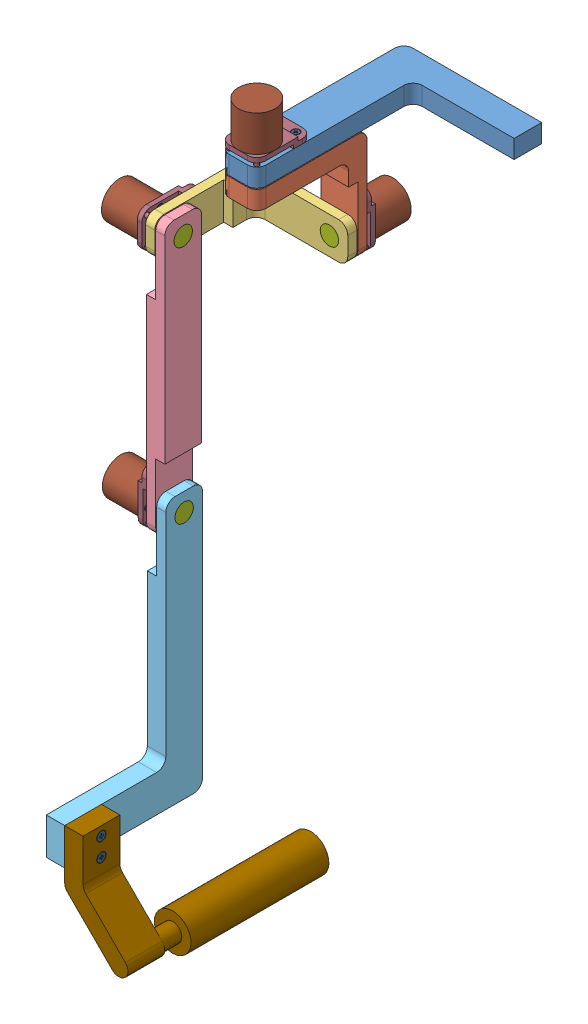
SolidWorks assembly master-arm, configuration Varsayılan. Lengths in mm.
Overall size (278 780.62 311).
52 component instances, 13 part files, 71 mates.
Components (placement in the parent):
- parca-1-1: parca-1 [Varsayılan] at (-105.8908 1.0153 205) x (1 0 0) z (0 1 0) size (150 200 20)
- parca-2-1: parca-2 [Varsayılan] at (-105.8908 -19.9847 230) size (40 120 120)
- parca-3-1: parca-3 [Varsayılan] at (-145.8908 -99.9847 171) size (120 40 120)
- parca-4-1: parca-4 [Varsayılan] at (-204.8908 -229.9847 271) size (20 300 40)
- parca-5-1: parca-5 [Varsayılan] at (-203.8908 -464.9847 271) size (20 290 150)
- pin-1-1: pin-1 [Varsayılan] at (-105.8908 -19.9847 270) size (20 40 20)
- pin-2-1: pin-2 [Varsayılan] at (-204.8908 -99.9847 271) size (20 20 20)
- pin-2-2: pin-2 [Varsayılan] at (-203.8908 -359.9847 271) size (20 20 20)
- pin-2-4: pin-2 [Varsayılan] at (-105.8908 -99.9847 171) x (0 0 1) z (-1 0 0) size (20 20 20)
- instrument ball bearing_68_am-1: instrument ball bearing_68_am [AFBMA 12.1.4.1 - 0200-27 - 28,SI,NC,28_68] at (-203.3908 -99.9847 271) x (-1 0 0) z (0 -0.924225 -0.381849) size (5 27 27)
- instrument ball bearing_68_am-4: instrument ball bearing_68_am [AFBMA 12.1.4.1 - 0200-27 - 28,SI,NC,28_68] at (-202.3908 -359.9847 271) x (-1 0 0) z (0 -0.924225 -0.381849) size (5 27 27)
- instrument ball bearing_68_am-5: instrument ball bearing_68_am [AFBMA 12.1.4.1 - 0200-27 - 28,SI,NC,28_68] at (-105.8908 -99.9847 172.5) x (0 0 -1) z (1 0 0) size (5 27 27)
- instrument ball bearing_68_am-6: instrument ball bearing_68_am [AFBMA 12.1.4.1 - 0200-27 - 28,SI,NC,28_68] at (-105.8908 18.5153 270) x (0 -1 0) z (0 0 1) size (5 27 27)
- parca-6-1: parca-6 [Varsayılan] at (-183.8908 -589.9847 361) x (1 0 0) z (0 -1 0) size (77.48 210 121.62)
- flat head screw_am-3: flat head screw_am [B18.6.7M - M5 x 0.8 x 30 Type I Cross Recessed FHMS --30N] at (-163.8908 -599.9847 381) x (-1 0 0) z (0 0 -1) size (30 9.3 9.3)
- flat head screw_am-4: flat head screw_am [B18.6.7M - M5 x 0.8 x 30 Type I Cross Recessed FHMS --30N] at (-163.8908 -619.9847 381) x (-1 0 0) z (0 0 -1) size (30 9.3 9.3)
- enkoder-1-1: enkoder-1 [Varsayılan] at (-216.6815 -102.4325 227) size (59 40 40)
  - enkoder-1: enkoder [Varsayılan] at (-37.2093 2.4478 44) size (44 40 40)
  - enkoder-mil-1: enkoder-mil [Varsayılan] at (1.7907 2.4478 44) size (20 6 6)
- enkoder-1-2: enkoder-1 [Varsayılan] at (-215.6815 -362.4325 227) size (59 40 40)
  - enkoder-1: enkoder [Varsayılan] at (-37.2093 2.4478 44) size (44 40 40)
  - enkoder-mil-1: enkoder-mil [Varsayılan] at (1.7907 2.4478 44) size (20 6 6)
- enkoder-1-3: enkoder-1 [Varsayılan] at (-61.8908 -102.4325 159.2093) x (0 0 1) z (-1 0 0) size (59 40 40)
  - enkoder-1: enkoder [Varsayılan] at (-37.2093 2.4478 44) size (44 40 40)
  - enkoder-mil-1: enkoder-mil [Varsayılan] at (1.7907 2.4478 44) size (20 6 6)
- enkoder-1-4: enkoder-1 [Varsayılan] at (-61.8908 31.806 267.5522) x (0 -1 0) z (-1 0 0) size (59 40 40)
  - enkoder-1: enkoder [Varsayılan] at (-37.2093 2.4478 44) size (44 40 40)
  - enkoder-mil-1: enkoder-mil [Varsayılan] at (1.7907 2.4478 44) size (20 6 6)
- enkoder-aparat-1: enkoder-aparat [Varsayılan] at (-214.8908 -99.9847 271) size (9 40 60)
- flat head screw_am-10: flat head screw_am [B18.6.7M - M3.5 x 0.6 x 10 Type I Cross Recessed FHMS --10N] at (-210.8408 -109.9847 239.1575) size (10 7.3 7.3)
- flat head screw_am-11: flat head screw_am [B18.6.7M - M3.5 x 0.6 x 10 Type I Cross Recessed FHMS --10N] at (-210.8408 -89.9847 239.1575) size (10 7.3 7.3)
- flat head screw_am-12: flat head screw_am [B18.6.7M - M3 x 0.5 x 13 Type I Cross Recessed FHMS --13N] at (-209.8408 -84.9847 271) x (-1 0 0) z (0 0 -1) size (13 5.5 5.5)
- flat head screw_am-13: flat head screw_am [B18.6.7M - M3 x 0.5 x 13 Type I Cross Recessed FHMS --13N] at (-209.8408 -107.4847 258.0096) x (-1 0 0) z (0 0 -1) size (13 5.5 5.5)
- flat head screw_am-14: flat head screw_am [B18.6.7M - M3 x 0.5 x 13 Type I Cross Recessed FHMS --13N] at (-209.8408 -107.4847 283.9904) x (-1 0 0) z (0 0 -1) size (13 5.5 5.5)
- enkoder-aparat-2: enkoder-aparat [Varsayılan] at (-213.8908 -359.9847 271) x (1 0 0) z (0 -1 0) size (9 40 60)
- flat head screw_am-15: flat head screw_am [B18.6.7M - M3.5 x 0.6 x 10 Type I Cross Recessed FHMS --10N] at (-209.8408 -327.4847 261) size (10 7.3 7.3)
- flat head screw_am-16: flat head screw_am [B18.6.7M - M3.5 x 0.6 x 10 Type I Cross Recessed FHMS --10N] at (-209.8408 -327.4847 281) size (10 7.3 7.3)
- enkoder-aparat-3: enkoder-aparat [Varsayılan] at (-105.8908 30.0153 270) x (0 -1 0) z (0 0 1) size (9 40 60)
- flat head screw_am-17: flat head screw_am [B18.6.7M - M3.5 x 0.6 x 10 Type I Cross Recessed FHMS --10N] at (-115.8908 25.9653 237.5) x (0 -1 0) z (0 0 1) size (10 7.3 7.3)
- flat head screw_am-18: flat head screw_am [B18.6.7M - M3.5 x 0.6 x 10 Type I Cross Recessed FHMS --10N] at (-95.8908 25.9653 237.5) x (0 -1 0) z (0 0 1) size (10 7.3 7.3)
- enkoder-aparat-4: enkoder-aparat [Varsayılan] at (-105.8908 -99.9847 161) x (0 0 1) z (0 -1 0) size (9 40 60)
- flat head screw_am-19: flat head screw_am [B18.6.7M - M3.5 x 0.6 x 10 Type I Cross Recessed FHMS --10N] at (-115.8908 -67.4847 165.05) x (0 0 1) z (-1 0 0) size (10 7.3 7.3)
- flat head screw_am-20: flat head screw_am [B18.6.7M - M3.5 x 0.6 x 10 Type I Cross Recessed FHMS --10N] at (-95.8908 -67.4847 165.05) x (0 0 1) z (-1 0 0) size (10 7.3 7.3)
- flat head screw_am-21: flat head screw_am [B18.6.7M - M3 x 0.5 x 6 Type I Cross Recessed FHMS --6N] at (-90.8908 24.9653 270) x (0 1 0) z (0 0 1) size (6 5.5 5.5)
- flat head screw_am-22: flat head screw_am [B18.6.7M - M3 x 0.5 x 6 Type I Cross Recessed FHMS --6N] at (-113.3908 24.9653 257.0096) x (0 1 0) z (0 0 1) size (6 5.5 5.5)
- flat head screw_am-23: flat head screw_am [B18.6.7M - M3 x 0.5 x 6 Type I Cross Recessed FHMS --6N] at (-113.3908 24.9653 282.9904) x (0 1 0) z (0 0 1) size (6 5.5 5.5)
- flat head screw_am-24: flat head screw_am [B18.6.7M - M3 x 0.5 x 6 Type I Cross Recessed FHMS --6N] at (-120.8908 -99.9847 166.05) x (0 0 -1) z (1 0 0) size (6 5.5 5.5)
- flat head screw_am-25: flat head screw_am [B18.6.7M - M3 x 0.5 x 6 Type I Cross Recessed FHMS --6N] at (-98.3908 -86.9943 166.05) x (0 0 -1) z (1 0 0) size (6 5.5 5.5)
- flat head screw_am-26: flat head screw_am [B18.6.7M - M3 x 0.5 x 6 Type I Cross Recessed FHMS --6N] at (-98.3908 -112.9751 166.05) x (0 0 -1) z (1 0 0) size (6 5.5 5.5)
- flat head screw_am-27: flat head screw_am [B18.6.7M - M3 x 0.5 x 6 Type I Cross Recessed FHMS --6N] at (-208.8408 -359.9847 286) x (-1 0 0) z (0 0 -1) size (6 5.5 5.5)
- flat head screw_am-28: flat head screw_am [B18.6.7M - M3 x 0.5 x 6 Type I Cross Recessed FHMS --6N] at (-208.8408 -346.9943 263.5) x (-1 0 0) z (0 0 -1) size (6 5.5 5.5)
- flat head screw_am-29: flat head screw_am [B18.6.7M - M3 x 0.5 x 6 Type I Cross Recessed FHMS --6N] at (-208.8408 -372.9751 263.5) x (-1 0 0) z (0 0 -1) size (6 5.5 5.5)
Mates (geometry in assembly coordinates):
- Concentric1: concentric aligned: circle of parca-1-1; circle of pin-1-1
- Concentric2: concentric aligned: circle of parca-2-1; circle of pin-1-1
- Concentric4: concentric anti-aligned: circle of parca-3-1; circle of pin-2-1
- Concentric5: concentric aligned: circle of parca-4-1; circle of pin-2-1
- Concentric6: concentric anti-aligned: circle of parca-4-1; circle of pin-2-2
- Concentric7: concentric aligned: circle of parca-5-1; circle of pin-2-2
- Concentric8: concentric anti-aligned: circle of parca-2-1; circle of pin-2-4
- Concentric9: concentric aligned: circle of parca-3-1; circle of pin-2-4
- Coincident15: coincident anti-aligned: plane of parca-2-1 through (-105.8908 -19.9847 230) normal (0 -1 0); circle of pin-1-1
- Coincident16: coincident aligned: plane of parca-4-1 through (-184.8908 -229.9847 271) normal (1 0 0); circle of pin-2-1
- Coincident24: coincident aligned: plane of parca-5-1 through (-183.8908 -464.9847 271) normal (1 0 0); plane of pin-2-2 through (-183.8908 -359.9847 271) normal (1 0 0)
- Coincident26: coincident aligned: circle of parca-3-1; circle of pin-2-4
- Concentric12: concentric aligned: cylinder of pin-2-1 through (-184.8908 -99.9847 271) axis (-1 0 0) radius 10; cylinder of instrument ball bearing_68_am-1 through (-182.7533 -99.9847 271) axis (-1 0 0) radius 10
- Coincident28: coincident aligned: plane of parca-3-1 through (-205.8908 -79.9847 191) normal (-1 0 0); plane of instrument ball bearing_68_am-1 through (-205.8908 -94.9061 258.7078) normal (-1 0 0)
- Concentric13: concentric aligned: cylinder of pin-2-2 through (-183.8908 -359.9847 271) axis (-1 0 0) radius 10; cylinder of instrument ball bearing_68_am-4 through (-181.7533 -359.9847 271) axis (-1 0 0) radius 10
- Distance1: distance = 0 mm aligned: plane of instrument ball bearing_68_am-4 through (-204.8908 -354.9061 258.7078) normal (-1 0 0); plane of parca-4-1 through (-204.8908 -229.9847 271) normal (-1 0 0)
- Concentric14: concentric aligned: cylinder of pin-2-4 through (-105.8908 -99.9847 191) axis (0 0 -1) radius 10; cylinder of instrument ball bearing_68_am-5 through (-105.8908 -99.9847 193.1375) axis (0 0 -1) radius 10
- Coincident32: coincident aligned: plane of parca-2-1 through (-125.8908 0.0153 170) normal (0 0 -1); plane of instrument ball bearing_68_am-5 through (-105.8908 -86.6847 170) normal (0 0 -1)
- Distance3: distance = 1 mm anti-aligned: plane of parca-3-1 through (-145.8908 -99.9847 181) normal (0 0 -1); plane of parca-2-1 through (-105.8908 -19.9847 180) normal (0 0 1)
- Concentric15: concentric aligned: cylinder of pin-1-1 through (-105.8908 20.0153 270) axis (0 -1 0) radius 10; cylinder of instrument ball bearing_68_am-6 through (-105.8908 39.1528 270) axis (0 -1 0) radius 10
- Distance4: distance = 0 mm aligned: plane of instrument ball bearing_68_am-6 through (-93.4408 21.0153 270) normal (0 1 0); plane of parca-1-1 through (-105.8908 21.0153 205) normal (0 1 0)
- Distance5: distance = 1 mm anti-aligned: plane of parca-2-1 through (-105.8908 0.0153 230) normal (0 1 0); plane of parca-1-1 through (-105.8908 1.0153 205) normal (0 -1 0)
- Distance9: distance = 1 mm anti-aligned: plane of parca-4-1 through (-194.8908 -229.9847 271) normal (1 0 0); plane of parca-5-1 through (-193.8908 -464.9847 271) normal (-1 0 0)
- Distance10: distance = 1 mm anti-aligned: plane of parca-3-1 through (-195.8908 -99.9847 171) normal (1 0 0); plane of parca-4-1 through (-194.8908 -229.9847 271) normal (-1 0 0)
- Parallel1: parallel aligned: plane of parca-5-1 through (-183.8908 -589.9847 401) normal (0 1 0); plane of parca-6-1 through (-183.8908 -589.9847 401) normal (0 1 0)
- Distance11: distance = 0 mm aligned: plane of parca-6-1 through (-183.8908 -589.9847 401) normal (0 1 0); plane of parca-5-1 through (-183.8908 -589.9847 401) normal (0 1 0)
- Distance12: distance = 0 mm aligned: plane of parca-6-1 through (-183.8908 -589.9847 401) normal (0 0 1); plane of parca-5-1 through (-203.8908 -464.9847 401) normal (0 0 1)
- Distance13: distance = 0 mm anti-aligned: plane of parca-5-1 through (-183.8908 -464.9847 271) normal (1 0 0); plane of parca-6-1 through (-183.8908 -648.269 401) normal (-1 0 0)
- Coincident33: coincident aligned: cone of parca-6-1 through (-163.8908 -599.9847 381) axis (-1 0 0); cone of flat head screw_am-3 through (-164.4408 -599.9847 381) axis (-1 0 0)
- Coincident34: coincident aligned: cone of parca-6-1 through (-163.8908 -619.9847 381) axis (-1 0 0); cone of flat head screw_am-4 through (-164.4408 -619.9847 381) axis (-1 0 0)
- Concentric17: concentric aligned: circle of pin-2-1; circle of enkoder-1-1/enkoder-1
- Concentric18: concentric aligned: circle of pin-2-4; circle of enkoder-1-3/enkoder-1
- Coincident38: coincident anti-aligned: plane of pin-2-1 through (-194.8908 -99.9847 271) normal (-1 0 0); plane of enkoder-1-1/enkoder-mil-1 through (-194.8908 -99.9847 271) normal (1 0 0)
- Coincident39: coincident anti-aligned: plane of pin-2-4 through (-105.8908 -99.9847 181) normal (0 0 -1); plane of enkoder-1-3/enkoder-mil-1 through (-105.8908 -99.9847 181) normal (0 0 1)
- Concentric19: concentric aligned: circle of pin-2-2; circle of enkoder-1-2/enkoder-1
- Coincident40: coincident anti-aligned: plane of pin-2-2 through (-193.8908 -359.9847 271) normal (-1 0 0); plane of enkoder-1-2/enkoder-mil-1 through (-193.8908 -359.9847 271) normal (1 0 0)
- Concentric20: concentric anti-aligned: circle of pin-1-1; circle of enkoder-1-4/enkoder-1
- Parallel2: parallel aligned: line of pin-1-1 through (-108.1269 20.0153 272) axis (1 0 0); line of enkoder-1-4/enkoder-mil-1 through (-108.1269 10.0153 272) axis (1 0 0)
- Coincident43: coincident anti-aligned: plane of pin-1-1 through (-105.8908 10.0153 270) normal (0 1 0); plane of enkoder-1-4/enkoder-mil-1 through (-105.8908 10.0153 270) normal (0 -1 0)
- Concentric21: concentric aligned: circle of enkoder-1-1/enkoder-1; circle of enkoder-aparat-1
- Coincident45: coincident anti-aligned: plane of enkoder-1-1/enkoder-1 through (-214.8908 -99.9847 271) normal (1 0 0); plane of enkoder-aparat-1 through (-214.8908 -109.9847 281) normal (-1 0 0)
- Coincident51: coincident aligned: cone of enkoder-aparat-1 through (-210.8908 -109.9847 239.1575) axis (1 0 0); cone of flat head screw_am-10 through (-210.4408 -109.9847 239.1575) axis (1 0 0)
- Coincident52: coincident aligned: cone of enkoder-aparat-1 through (-210.8908 -89.9847 239.1575) axis (1 0 0); cone of flat head screw_am-11 through (-210.4408 -89.9847 239.1575) axis (1 0 0)
- Coincident53: coincident aligned: cone of enkoder-aparat-1 through (-209.8908 -84.9847 271) axis (-1 0 0); cone of flat head screw_am-12 through (-210.2908 -84.9847 271) axis (-1 0 0)
- Coincident54: coincident aligned: cone of enkoder-aparat-1 through (-209.8908 -107.4847 258.0096) axis (-1 0 0); cone of flat head screw_am-13 through (-210.2908 -107.4847 258.0096) axis (-1 0 0)
- Coincident55: coincident aligned: cone of enkoder-aparat-1 through (-209.8908 -107.4847 283.9904) axis (-1 0 0); cone of flat head screw_am-14 through (-210.2908 -107.4847 283.9904) axis (-1 0 0)
- Concentric22: concentric aligned: circle of enkoder-1-2/enkoder-1; circle of enkoder-aparat-2
- Distance15: distance = 0 mm anti-aligned: plane of enkoder-aparat-2 through (-204.8908 -374.9847 256) normal (1 0 0); plane of parca-4-1 through (-204.8908 -229.9847 271) normal (-1 0 0)
- Parallel4: parallel aligned: line of parca-4-1 through (-204.8908 -379.9847 281) axis (0 0 -1); line of enkoder-aparat-2 through (-208.8908 -379.9847 281) axis (0 0 -1)
- Coincident60: coincident aligned: cone of enkoder-aparat-2 through (-209.8908 -327.4847 261) axis (1 0 0); cone of flat head screw_am-15 through (-209.4408 -327.4847 261) axis (1 0 0)
- Coincident61: coincident aligned: cone of enkoder-aparat-2 through (-209.8908 -327.4847 281) axis (1 0 0); cone of flat head screw_am-16 through (-209.4408 -327.4847 281) axis (1 0 0)
- Concentric23: concentric aligned: circle of enkoder-1-4/enkoder-1; circle of enkoder-aparat-3
- Distance16: distance = 0 mm anti-aligned: plane of enkoder-aparat-3 through (-115.8908 30.0153 280) normal (0 1 0); plane of enkoder-1-4/enkoder-1 through (-105.8908 30.0153 270) normal (0 -1 0)
- Parallel5: parallel aligned: line of parca-3-1 through (-205.8908 -89.9847 291) axis (0 -1 0); line of enkoder-aparat-1 through (-209.8908 -89.9847 291) axis (0 -1 0)
- Parallel6: parallel anti-aligned: line of parca-1-1 through (-115.8908 21.0153 290) axis (1 0 0); line of enkoder-aparat-3 through (-95.8908 30.0153 290) axis (-1 0 0)
- Coincident66: coincident aligned: cone of enkoder-aparat-3 through (-115.8908 26.0153 237.5) axis (0 -1 0); cone of flat head screw_am-17 through (-115.8908 25.5653 237.5) axis (0 -1 0)
- Coincident67: coincident aligned: cone of enkoder-aparat-3 through (-95.8908 26.0153 237.5) axis (0 -1 0); cone of flat head screw_am-18 through (-95.8908 25.5653 237.5) axis (0 -1 0)
- Concentric24: concentric aligned: circle of enkoder-1-3/enkoder-1; circle of enkoder-aparat-4
- Distance17: distance = 0 mm anti-aligned: plane of enkoder-aparat-4 through (-95.8908 -109.9847 161) normal (0 0 -1); plane of enkoder-1-3/enkoder-1 through (-105.8908 -99.9847 161) normal (0 0 1)
- Parallel7: parallel aligned: line of parca-2-1 through (-115.8908 -119.9847 170) axis (1 0 0); line of enkoder-aparat-4 through (-115.8908 -119.9847 161) axis (1 0 0)
- Coincident71: coincident aligned: cone of enkoder-aparat-4 through (-115.8908 -67.4847 165) axis (0 0 1); cone of flat head screw_am-19 through (-115.8908 -67.4847 165.45) axis (0 0 1)
- Coincident72: coincident aligned: cone of enkoder-aparat-4 through (-95.8908 -67.4847 165) axis (0 0 1); cone of flat head screw_am-20 through (-95.8908 -67.4847 165.45) axis (0 0 1)
- Coincident73: coincident aligned: cone of enkoder-aparat-3 through (-90.8908 25.0153 270) axis (0 1 0); cone of flat head screw_am-21 through (-90.8908 25.4153 270) axis (0 1 0)
- Coincident74: coincident aligned: cone of enkoder-aparat-3 through (-113.3908 25.0153 257.0096) axis (0 1 0); cone of flat head screw_am-22 through (-113.3908 25.4153 257.0096) axis (0 1 0)
- Coincident75: coincident aligned: cone of enkoder-aparat-3 through (-113.3908 25.0153 282.9904) axis (0 1 0); cone of flat head screw_am-23 through (-113.3908 25.4153 282.9904) axis (0 1 0)
- Coincident76: coincident aligned: cone of enkoder-aparat-4 through (-120.8908 -99.9847 166) axis (0 0 -1); cone of flat head screw_am-24 through (-120.8908 -99.9847 165.6) axis (0 0 -1)
- Coincident77: coincident aligned: cone of enkoder-aparat-4 through (-98.3908 -86.9943 166) axis (0 0 -1); cone of flat head screw_am-25 through (-98.3908 -86.9943 165.6) axis (0 0 -1)
- Coincident78: coincident aligned: cone of enkoder-aparat-4 through (-98.3908 -112.9751 166) axis (0 0 -1); cone of flat head screw_am-26 through (-98.3908 -112.9751 165.6) axis (0 0 -1)
- Coincident79: coincident aligned: cone of enkoder-aparat-2 through (-208.8908 -359.9847 286) axis (-1 0 0); cone of flat head screw_am-27 through (-209.2908 -359.9847 286) axis (-1 0 0)
- Coincident80: coincident aligned: cone of enkoder-aparat-2 through (-208.8908 -346.9943 263.5) axis (-1 0 0); cone of flat head screw_am-28 through (-209.2908 -346.9943 263.5) axis (-1 0 0)
- Coincident81: coincident aligned: cone of enkoder-aparat-2 through (-208.8908 -372.9751 263.5) axis (-1 0 0); cone of flat head screw_am-29 through (-209.2908 -372.9751 263.5) axis (-1 0 0)
